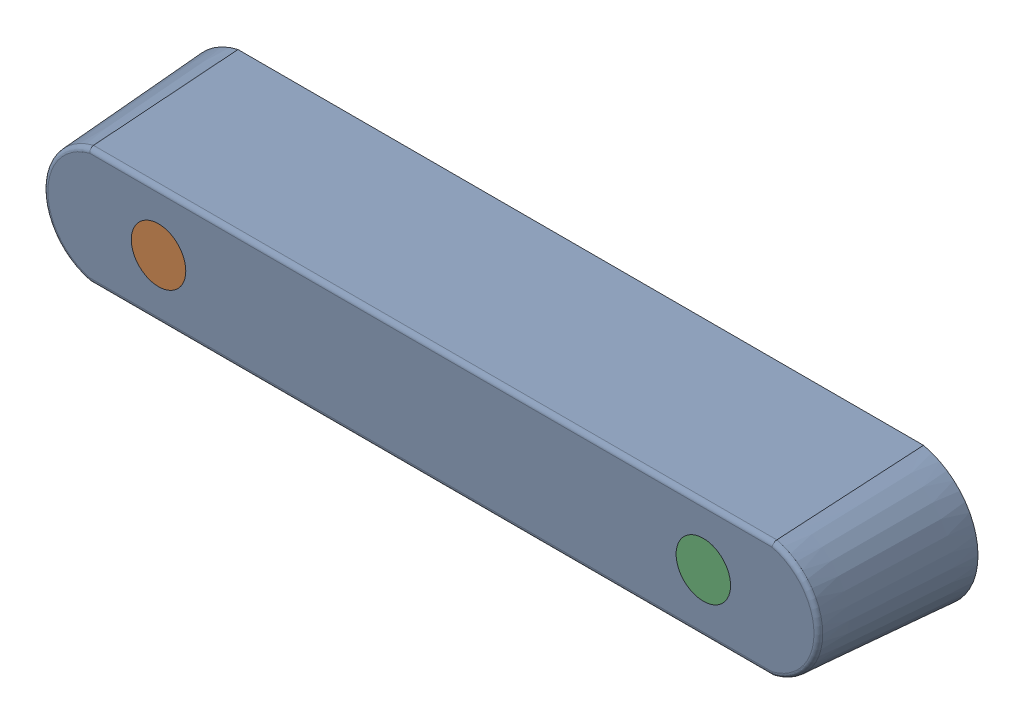
SolidWorks assembly ZED-camera, configuration Default. Lengths in mm.
Overall size (175 30 38).
3 component instances, 2 part files, 2 mates.
Components (placement in the parent):
- ZED-Body-1: ZED-Body [Default] at origin size (175 30 38)
- ZED-Glass-1: ZED-Glass [Default] at (-60 0 31) size (12 12 2)
- ZED-Glass-2: ZED-Glass [Default] at (60 0 31) size (12 12 2)
Mates (geometry in assembly coordinates):
- Coincidente2: coincident aligned: circle of ZED-Body-1; circle of ZED-Glass-1
- Coincidente3: coincident aligned: circle of ZED-Body-1; circle of ZED-Glass-2
